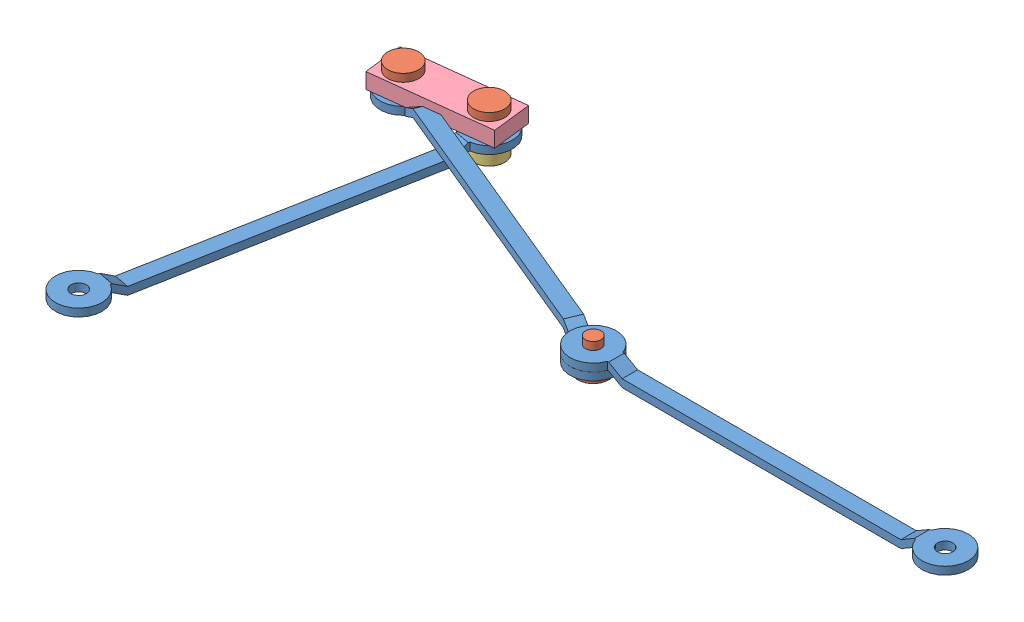
SolidWorks assembly Assemble 1, configuration Default. Lengths in mm.
Overall size (94.37 6 51.69).
10 component instances, 5 part files, 18 mates.
Components (placement in the parent):
- arm new-1: arm new [Default] at (28.2278 24.0247 45.3736) size (51.46 2 6)
- arm new-2: arm new [Default] at (-15.8801 26.0247 38.5749) x (0.923459 0 0.383697) z (0.383697 0 -0.923459) size (51.46 2 6)
- bolt neww-1: bolt neww [Default] at (5.4957 23.0247 46.3736) size (4 4 4)
- Part1^Assemble 1-1: Part1^Assemble 1 [Default] at origin (virtual)
- arm new-3: arm new [Default] at (-29.742 23.0247 50.2969) x (-0.183387 0 0.983041) z (-0.983041 0 -0.183387) size (51.46 2 6)
- bolt new-1: bolt new [Default] at (-36.4885 24.8747 28.9292) size (4 2 4)
- bolt neww-2: bolt neww [Default] at (-26.5563 28.0247 27.767) x (-0.837169 0 -0.546944) z (-0.546944 0 0.837169) size (4 4 4)
- tyer pad-1: tyer pad [Default] at (-31.1868 25.0247 27.4204) x (-0.993224 0 0.116219) z (0.116219 0 0.993224) size (15 2 5)
- bolt neww-3: bolt neww [Default] at (-36.4885 28.0247 28.9292) x (-0.837169 0 -0.546944) z (-0.546944 0 0.837169) size (4 4 4)
- bolt new-3: bolt new [Default] at (-26.5563 22.0247 27.767) size (4 2 4)
Mates (geometry in assembly coordinates):
- Coincident1: coincident: cylinder of arm new-1 through (5.4957 24.0247 46.3736) axis (0 1 0) radius 1; circle of arm new-1
- Concentric1: concentric: cylinder of arm new-1 through (5.4957 24.0247 46.3736) axis (0 1 0) radius 1; cylinder of bolt neww-1 through (5.4957 27.0247 46.3736) axis (0 -1 0) radius 1
- Coincident4: coincident: plane of arm new-2 through (3.109 24.0247 44.2991) normal (0 -1 0); plane of bolt neww-1 through (5.4957 24.0247 46.3736) normal (0 1 0)
- Coincident6: coincident: circle of arm new-1; circle of arm new-2
- Concentric2: concentric: cylinder of arm new-2 through (-36.4885 26.0247 28.9292) axis (0 -1 0) radius 1; circle of tyer pad-1
- Parallel1: parallel: cylinder of arm new-2 through (-36.4885 26.0247 28.9292) axis (0 -1 0) radius 1; cylinder of tyer pad-1 through (-26.5563 27.0247 27.767) axis (0 -1 0) radius 1.4595
- Coincident7: coincident: circle of arm new-2; plane of tyer pad-1 through (-31.1868 25.0247 27.4204) normal (0 -1 0)
- Coincident8: coincident: circle of arm new-2; plane of tyer pad-1 through (-31.1868 25.0247 27.4204) normal (0 -1 0)
- Concentric6: concentric: cylinder of tyer pad-1 through (-36.4885 27.0247 28.9292) axis (0 -1 0) radius 1.4595; circle of bolt neww-3
- Coincident10: coincident: circle of tyer pad-1; plane of bolt neww-3 through (-36.4885 27.0247 28.9292) normal (0 -1 0)
- Concentric8: concentric: circle of bolt new-1; circle of bolt neww-3
- Concentric9: concentric: circle of arm new-3; circle of tyer pad-1
- Concentric10: concentric: circle of bolt neww-2; circle of tyer pad-1
- Coincident11: coincident: plane of arm new-3 through (-28.0895 24.0247 30.5327) normal (0 -1 0); circle of arm new-3
- Coincident13: coincident: plane of arm new-3 through (-28.0895 25.0247 30.5327) normal (0 1 0); circle of tyer pad-1
- Coincident14: coincident: plane of bolt neww-2 through (-26.5563 24.0247 27.767) normal (0 -1 0); plane of bolt new-3 through (-26.5563 24.0247 27.767) normal (0 1 0)
- Concentric15: concentric: circle of bolt neww-2; circle of bolt new-3
- Coincident16: coincident: plane of arm new-3 through (-28.0895 24.0247 30.5327) normal (0 -1 0); plane of bolt new-3 through (-26.5563 24.0247 27.767) normal (0 1 0)
